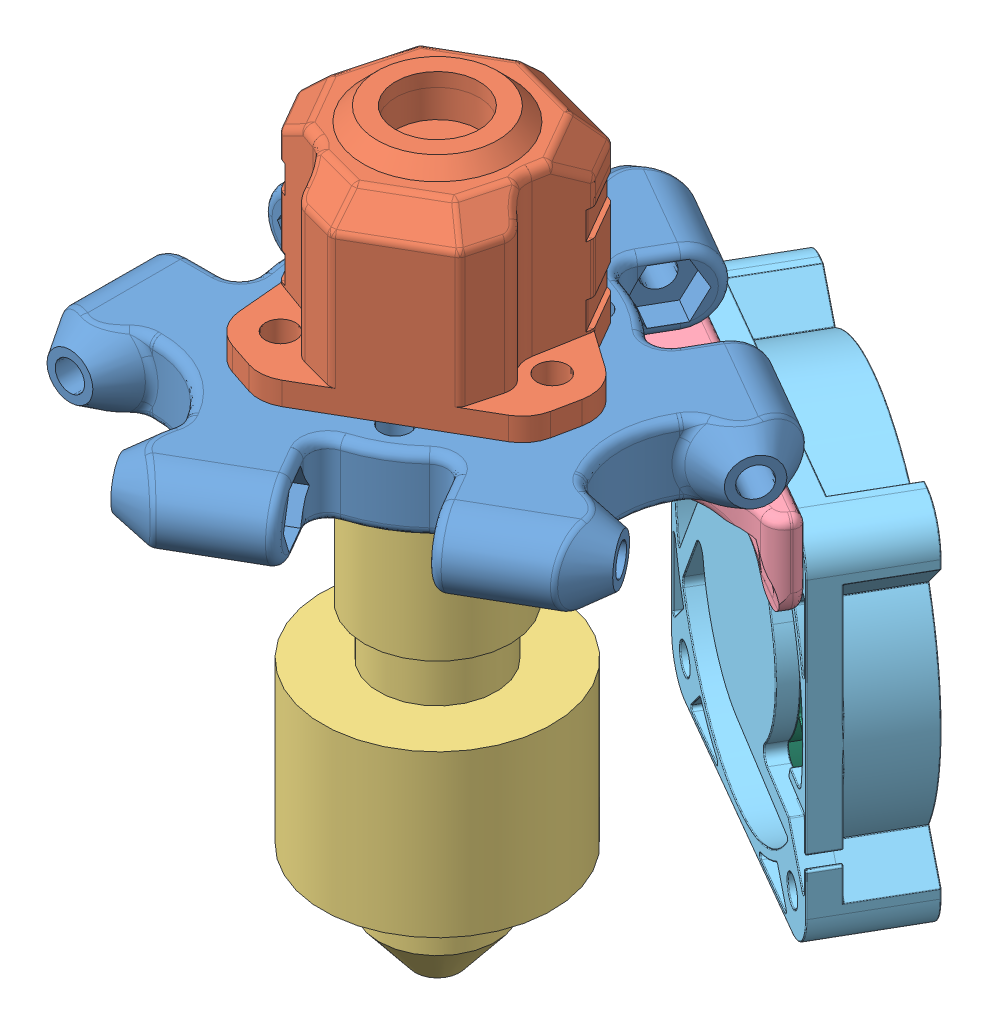
SolidWorks assembly assembled_hotend_ubis, configuration Default. Lengths in mm.
Overall size (59.84 80.54 70.03).
10 component instances, 8 part files, 22 mates.
Components (placement in the parent):
- effector-1: effector [UBIS] at origin size (53.68 8.59 59.75)
- ubis_holder-1: ubis_holder [side 1] at (0 4 0) x (0.866025 0 -0.5) z (0.5 0 0.866025) size (29.95 21.5 25)
- ubis_holder-2: ubis_holder [side 2] at (0 4 0) x (0.866025 0 -0.5) z (0.5 0 0.866025) size (25 15 16.65)
- ubis hotend-1: ubis hotend [Default] at (0 19 0) size (25 74.04 25)
- effector_fan_40mm-1: effector_fan_40mm [Default] at (0 -4 0) x (-1 0 0) z (0 -1 0) size (38.7 33.92 10.03)
- 40mm-fan-1: 40mm-fan [По умолчанию] at (14.3045 -33.0036 -22.9182) x (-0.866025 0 -0.5) z (0.5 0 -0.866025) size (40.01 40.11 10.82)
  - body^40mm-fan-1: body^40mm-fan [По умолчанию] at (0.9289 7.0036 0) size (40.01 40.11 10.81) (virtual)
  - blades^40mm-fan-1: blades^40mm-fan [По умолчанию] at (0.9289 7.0036 -1) size (37.4 37 9.12) (virtual)
- 50x15_blower_fan_20mm_opening-1: 50x15_blower_fan_20mm_opening [Default] at (-32.734 -12.89 56.697) x (0.167485 0.942229 -0.290092) z (0.866025 0 0.5) (suppressed, hidden)
- Part16^assembled_hotend_ubis-1: Part16^assembled_hotend_ubis [Default] at (0 -4 0) x (-1 0 0) z (0 -1 0) (suppressed, hidden, virtual)
Mates (geometry in assembly coordinates):
- Coincident1: coincident anti-aligned: plane of effector-1 through (-15 4 25.9808) normal (0 1 0); plane of ubis_holder-1 through (0 4 0) normal (0 -1 0)
- Concentric1: concentric anti-aligned: cylinder of effector-1 through (-6.25 -4 10.8253) axis (0 1 0) radius 1.6; cylinder of ubis_holder-1 through (-6.25 6.5 10.8253) axis (0 -1 0) radius 1.65
- Concentric2: concentric anti-aligned: cylinder of effector-1 through (12.5 -4 0) axis (0 1 0) radius 1.6; cylinder of ubis_holder-1 through (12.5 6.5 0) axis (0 -1 0) radius 1.65
- Coincident2: coincident anti-aligned: plane of effector-1 through (-15 4 25.9808) normal (0 1 0); plane of ubis_holder-2 through (0 4 0) normal (0 -1 0)
- Concentric3: concentric anti-aligned: cylinder of effector-1 through (-6.25 -4 -10.8253) axis (0 1 0) radius 1.6; cylinder of ubis_holder-2 through (-6.25 6.5 -10.8253) axis (0 -1 0) radius 1.65
- Coincident3: coincident anti-aligned: plane of ubis_holder-1 through (0 4 0) normal (-0.5 0 -0.866025); plane of ubis_holder-2 through (0 4 0) normal (0.5 0 0.866025)
- Coincident4: coincident anti-aligned: plane of ubis_holder-1 through (-0.866 19 0.5) normal (0 -1 0); plane of ubis hotend-1 through (0 19 0) normal (0 1 0)
- Concentric4: concentric aligned: cylinder of ubis_holder-1 through (0 -20.1617 0) axis (0 -1 0) radius 1; cylinder of ubis hotend-1 through (0 19 0) axis (0 -1 0) radius 7.9629
- InPlace1: in place: plane of effector-1 through (-15 -4 25.9808) normal (0 -1 0); plane of ? through (0 -4 0) normal (0 -1 0); moOrthogonalPlaneRef_w of effector-1 through (-15 -4 25.9808) normal (0 -1 0); unknown of ?; plane of effector-1 through (-15 -4 25.9808) normal (0 -1 0); line of ? through (-55 0 -4) axis (0 -1 0); plane of effector-1 through (-15 -4 25.9808) normal (0 -1 0); unknown of ?
- Coincident5: coincident aligned: plane of assembly through (0 0 0) normal (0 0 1)
- Coincident6: coincident aligned: moOrthogonalPlaneRef_w of effector-1 through (0 -4 0) normal (0 0 -1); plane of effector_fan_40mm-1
- Coincident7: coincident anti-aligned: moOrthogonalPlaneRef_w of effector-1 through (0 -4 0) normal (1 0 0); plane of effector_fan_40mm-1
- Coincident5: coincident anti-aligned: plane of effector_fan_40mm-1 through (29.3205 -6 -10.7846) normal (0.5 0 -0.866025); plane of 40mm-fan-1/body^40mm-fan-1 through (21.9148 -44.9446 -15.0603) normal (-0.5 0 0.866025)
- Concentric5: concentric anti-aligned: cylinder of effector_fan_40mm-1 through (23.3564 -10 -8.4545) axis (0.5 0 -0.866025) radius 1.5; cylinder of 40mm-fan-1/body^40mm-fan-1 through (29.8064 -10 -19.6262) axis (-0.5 0 0.866025) radius 1.5
- Coincident6: coincident anti-aligned: circle of effector_fan_40mm-1; cylinder of 40mm-fan-1/body^40mm-fan-1 through (2.0936 -10 -35.6262) axis (-0.5 0 0.866025) radius 1.5
- InPlace2: in place: plane of effector-1 through (-15 -4 25.9808) normal (0 -1 0); plane of ? through (0 -4 0) normal (0 -1 0); plane of effector-1 through (-15 -4 25.9808) normal (0 -1 0); unknown of ?; plane of effector-1 through (-15 -4 25.9808) normal (0 -1 0); line of ? through (-55 0 -4) axis (0 -1 0); plane of effector-1 through (-15 -4 25.9808) normal (0 -1 0); unknown of ?
- Coincident7: coincident aligned: plane of effector-1; plane of Part16^assembled_hotend_ubis-1
- Coincident8: coincident aligned: moOrthogonalPlaneRef_w of effector-1 through (0 -4 0) normal (0 0 -1); plane of Part16^assembled_hotend_ubis-1
- Coincident9: coincident anti-aligned: moOrthogonalPlaneRef_w of effector-1 through (0 -4 0) normal (1 0 0); plane of Part16^assembled_hotend_ubis-1
- Coincident12: coincident anti-aligned: plane of 50x15_blower_fan_20mm_opening-1 through (-19.227 6.0799 48.3022) normal (0.866025 0 0.5); plane of Part16^assembled_hotend_ubis-1 through (-14.5144 -6 40.1397) normal (-0.866025 0 -0.5)
- Coincident13: coincident anti-aligned: plane of 50x15_blower_fan_20mm_opening-1 through (-32.2174 6.0799 40.8022) normal (-0.866025 0 -0.5); plane of Part16^assembled_hotend_ubis-1 through (-27.5048 -6 32.6397) normal (0.866025 0 0.5)
- Concentric8: concentric aligned: cylinder of 50x15_blower_fan_20mm_opening-1 through (-27.5048 0 32.6397) axis (0.866025 0 0.5) radius 2.25; cylinder of Part16^assembled_hotend_ubis-1 through (-30.9689 0 30.6397) axis (0.866025 0 0.5) radius 2.25
